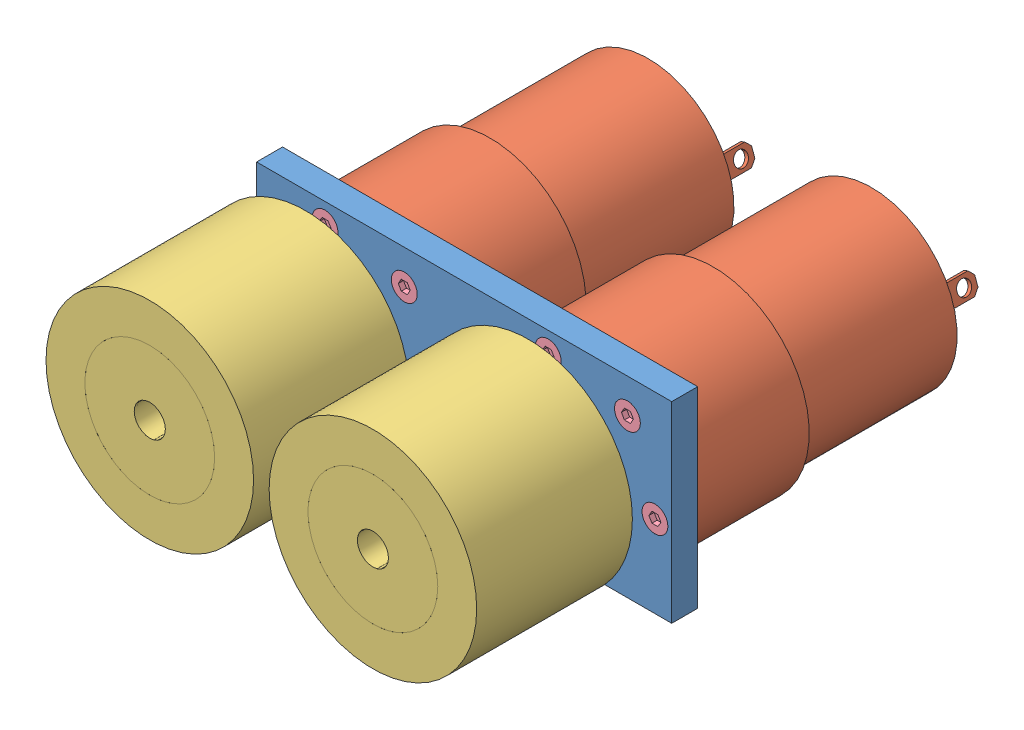
SolidWorks assembly Ruedas_D, configuration Predeterminado. Lengths in mm.
Overall size (88.08 41.65 151.25).
17 component instances, 4 part files, 22 mates.
Components (placement in the parent):
- Bracket_Motor_D-1: Bracket_Motor_D [Predeterminado] at (-5.4362 4.6538 77.5) size (85 37 5)
- Titan-37mm-500rpm-2: Titan-37mm-500rpm [Predeterminado] at (16.0638 4.6538 56) x (0.34202 -0.939693 0) z (0 0 1) size (37 37 78.75)
- Titan-37mm-500rpm-3: Titan-37mm-500rpm [Predeterminado] at (-26.9341 4.6545 56) x (0.34202 -0.939693 0) z (0 0 1) size (37 37 78.75)
- js4030-wheel-cad-1: js4030-wheel-cad [Predeterminado] at (-53.7606 2.8053 140) x (-1 0 0) z (0 0 -1) size (40 40 30)
- js4030-wheel-cad-2: js4030-wheel-cad [Predeterminado] at (-10.7627 2.8046 140) x (-1 0 0) z (0 0 -1) size (40 40 30)
- Tornillo M3x15-1: Tornillo M3x15 [Predeterminado] at (-42.2008 7.3453 67.5) size (5 5 15.24)
- Tornillo M3x15-2: Tornillo M3x15 [Predeterminado] at (-32.2376 19.219 67.5) size (5 5 15.24)
- Tornillo M3x15-4: Tornillo M3x15 [Predeterminado] at (-21.6349 -9.9115 67.5) size (5 5 15.24)
- Tornillo M3x15-5: Tornillo M3x15 [Predeterminado] at (-36.8995 -7.2199 67.5) size (5 5 15.24)
- Tornillo M3x15-6: Tornillo M3x15 [Predeterminado] at (-16.973 16.5274 67.5) size (5 5 15.24)
- Tornillo M3x15-7: Tornillo M3x15 [Predeterminado] at (-11.6717 1.9622 67.5) size (5 5 15.24)
- Tornillo M3x15-8: Tornillo M3x15 [Predeterminado] at (6.1005 -7.2199 67.5) size (5 5 15.24)
- Tornillo M3x15-9: Tornillo M3x15 [Predeterminado] at (31.3283 1.9622 67.5) size (5 5 15.24)
- Tornillo M3x15-10: Tornillo M3x15 [Predeterminado] at (21.3651 -9.9115 67.5) size (5 5 15.24)
- Tornillo M3x15-11: Tornillo M3x15 [Predeterminado] at (0.7992 7.3453 67.5) size (5 5 15.24)
- Tornillo M3x15-12: Tornillo M3x15 [Predeterminado] at (26.027 16.5274 67.5) size (5 5 15.24)
- Tornillo M3x15-13: Tornillo M3x15 [Predeterminado] at (10.7624 19.219 67.5) size (5 5 15.24)
Mates (geometry in assembly coordinates):
- Coincidente4: coincident anti-aligned: plane of Bracket_Motor_D-1 through (-5.4362 4.6538 77.5) normal (0 0 -1); plane of Titan-37mm-500rpm-2 through (16.0638 4.6538 77.5) normal (0 0 1)
- Coincidente5: coincident anti-aligned: plane of Bracket_Motor_D-1 through (-5.4362 4.6538 77.5) normal (0 0 -1); plane of Titan-37mm-500rpm-3 through (-26.9341 4.6545 77.5) normal (0 0 1)
- Concéntrica3: concentric aligned: cylinder of Bracket_Motor_D-1 through (-33.5141 2.2596 77.5) axis (0 0 1) radius 6; cylinder of Titan-37mm-500rpm-3 through (-33.5141 2.2596 77.5) axis (0 0 1) radius 6
- Distancia1: distance = 1.5 mm aligned: plane of js4030-wheel-cad-2 through (9.4837 2.2588 85) normal (0 0 1); plane of Titan-37mm-500rpm-2 through (9.4837 2.2588 83.5) normal (0 0 1)
- Tangente1: tangent aligned: cylinder of js4030-wheel-cad-2 through (9.4837 2.2588 85) axis (0 0 1) radius 3; cylinder of Titan-37mm-500rpm-2 through (9.4837 2.2588 83.5) axis (0 0 1) radius 3
- Coincidente7: coincident aligned: plane of js4030-wheel-cad-1 through (-33.5141 2.2596 85) normal (0 0 -1); plane of js4030-wheel-cad-2 through (9.4837 2.2588 85) normal (0 0 -1)
- Concéntrica4: concentric aligned: cylinder of Titan-37mm-500rpm-3 through (-33.5141 2.2596 83.5) axis (0 0 1) radius 3; cylinder of js4030-wheel-cad-1 through (-33.5141 2.2596 85) axis (0 0 1) radius 3
- Coincidente9: coincident aligned: cone of Bracket_Motor_D-1 through (-42.2008 7.3453 80.5) axis (0 0 -1); cone of Tornillo M3x15-1 through (-42.2008 7.3453 82) axis (0 0 -1)
- Coincidente10: coincident aligned: cone of Bracket_Motor_D-1 through (-32.2376 19.219 80.5) axis (0 0 -1); cone of Tornillo M3x15-2 through (-32.2376 19.219 82) axis (0 0 -1)
- Coincidente11: coincident aligned: cone of Bracket_Motor_D-1 through (-16.973 16.5274 80.5) axis (0 0 -1); cone of Tornillo M3x15-6 through (-16.973 16.5274 82) axis (0 0 -1)
- Coincidente13: coincident aligned: cone of Bracket_Motor_D-1 through (-21.6349 -9.9115 80.5) axis (0 0 -1); cone of Tornillo M3x15-4 through (-21.6349 -9.9115 82) axis (0 0 -1)
- Coincidente14: coincident aligned: cone of Bracket_Motor_D-1 through (-36.8995 -7.2199 80.5) axis (0 0 -1); cone of Tornillo M3x15-5 through (-36.8995 -7.2199 82) axis (0 0 -1)
- Coincidente15: coincident aligned: cone of Bracket_Motor_D-1 through (-11.6717 1.9622 80.5) axis (0 0 -1); cone of Tornillo M3x15-7 through (-11.6717 1.9622 82) axis (0 0 -1)
- Coincidente16: coincident aligned: cone of Bracket_Motor_D-1 through (21.3651 -9.9115 80.5) axis (0 0 -1); cone of Tornillo M3x15-10 through (21.3651 -9.9115 82) axis (0 0 -1)
- Coincidente17: coincident aligned: cone of Bracket_Motor_D-1 through (31.3283 1.9622 80.5) axis (0 0 -1); cone of Tornillo M3x15-9 through (31.3283 1.9622 82) axis (0 0 -1)
- Coincidente18: coincident aligned: cone of Bracket_Motor_D-1 through (0.7992 7.3453 80.5) axis (0 0 -1); cone of Tornillo M3x15-11 through (0.7992 7.3453 82) axis (0 0 -1)
- Coincidente19: coincident aligned: cone of Bracket_Motor_D-1 through (6.1005 -7.2199 80.5) axis (0 0 -1); cone of Tornillo M3x15-8 through (6.1005 -7.2199 82) axis (0 0 -1)
- Coincidente20: coincident aligned: cone of Bracket_Motor_D-1 through (26.027 16.5274 80.5) axis (0 0 -1); cone of Tornillo M3x15-12 through (26.027 16.5274 82) axis (0 0 -1)
- Coincidente21: coincident aligned: cone of Bracket_Motor_D-1 through (10.7624 19.219 80.5) axis (0 0 -1); cone of Tornillo M3x15-13 through (10.7624 19.219 82) axis (0 0 -1)
- Coincidente22: coincident anti-aligned: plane of Bracket_Motor_D-1 through (-45.4362 23.1538 82.5) normal (0 1 0); plane of ? through (14.5638 23.1538 42.5) normal (0 -1 0)
- Coincidente23: coincident aligned: plane of Bracket_Motor_D-1 through (-5.4362 4.6538 82.5) normal (0 0 1); plane of ? through (-45.4362 26.1538 82.5) normal (0 0 1)
- Coincidente24: coincident aligned: plane of Bracket_Motor_D-1 through (-45.4362 -13.8462 82.5) normal (-1 0 0); plane of ? through (-45.4362 26.1538 82.5) normal (-1 0 0)
